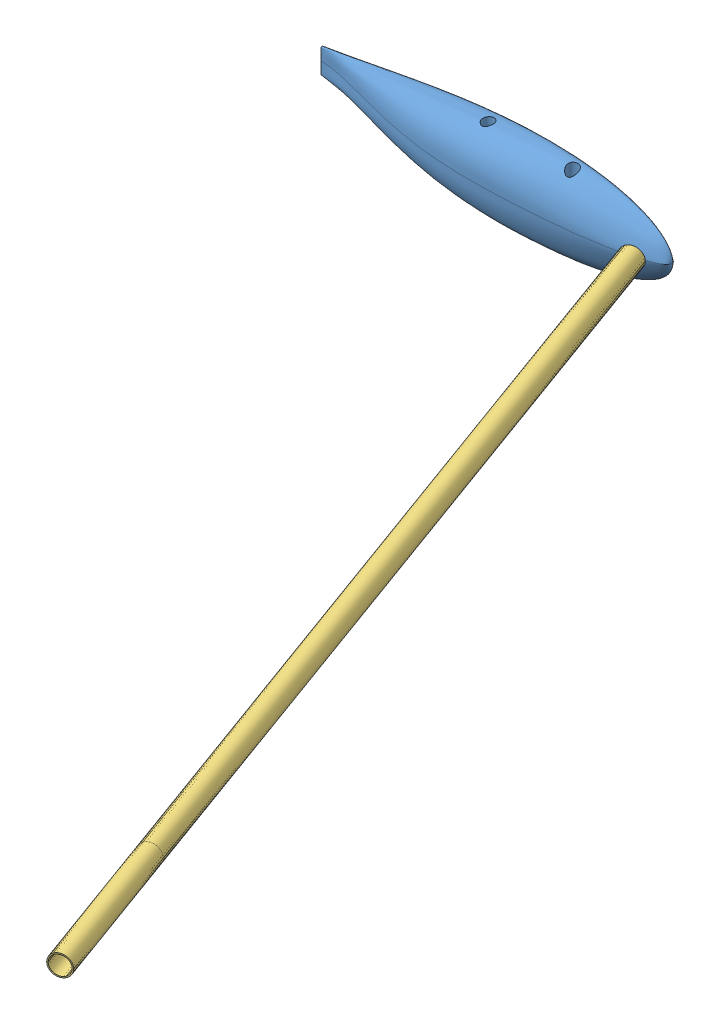
SolidWorks assembly RoundKeelCoreTest, configuration FEA. Lengths in mm.
Overall size (897.28 111.3 1260.6).
4 component instances, 3 part files, 15 mates.
Components (placement in the parent):
- Keel_bulb_Wide-1: Keel_bulb_Wide [Default] x (-1 0 0) z (0 0 -1)
- Keel_bulb_Wide-2: Keel_bulb_Wide [RightHalf] x (-1 0 0) z (0 0 -1)
- Keel_bulb_support-1: Keel_bulb_support [Default<As Machined>] at (-41.8863 0 0) x (1 0 0) z (0 -1 0)
- RoundKeelCore-1: RoundKeelCore [Default] at (-34.1794 0 21.1744) x (0 1 0) z (0.939693 0 -0.34202)
Mates (geometry in assembly coordinates):
- Coincident46: coincident anti-aligned: plane of Keel_bulb_Wide-1 through (-474.98 0 -1.2536) normal (0 -1 0); plane of Keel_bulb_Wide-2 through (-474.98 0 -1.2536) normal (0 1 0)
- Coincident145: coincident anti-aligned: plane of ? through (-25.4428 10.6172 17.3288) normal (0 -1 0); plane of Keel_bulb_support-1 through (-43.0589 10.6172 -31.071) normal (0 1 0)
- Parallel1: parallel anti-aligned: plane of ? through (-25.4428 10.6172 17.3288) normal (-0.939693 0 0.34202); plane of Keel_bulb_support-1 through (-43.0589 10.6172 -31.071) normal (0.939693 0 -0.34202)
- Concentric4: concentric anti-aligned: cylinder of ? through (-29.477 -10.8585 35.6909) axis (0 -1 0) radius 3.3782; cylinder of Keel_bulb_support-1 through (-29.477 10.6172 35.6909) axis (0 1 0) radius 2.0193
- Coincident148: coincident anti-aligned: plane of Keel_bulb_Wide-1 through (-41.8863 0 0) normal (0 0 1); plane of Keel_bulb_support-1 through (-41.8863 0 0) normal (0 0 -1)
- Coincident149: coincident anti-aligned: plane of Keel_bulb_Wide-1 through (-42.4457 9.525 -29.3861) normal (-0.939693 0 0.34202); plane of Keel_bulb_support-1 through (-42.4457 9.525 -29.3861) normal (0.939693 0 -0.34202)
- Coincident150: coincident anti-aligned: plane of Keel_bulb_Wide-2 through (-7.4567 3.3274 0) normal (0 0 1); plane of Keel_bulb_support-1 through (-41.8863 0 0) normal (0 0 -1)
- Coincident151: coincident anti-aligned: plane of Keel_bulb_Wide-2 through (-42.4457 9.525 -29.3861) normal (-0.939693 0 0.34202); plane of Keel_bulb_support-1 through (-42.4457 9.525 -29.3861) normal (0.939693 0 -0.34202)
- Coincident161: coincident anti-aligned: plane of Keel_bulb_Wide-1 through (-7.4567 3.3274 0) normal (0 -1 0); plane of Keel_bulb_support-1 through (-7.4567 3.3274 0) normal (0 1 0)
- Coincident163: coincident: point of ?
- Coincident164: coincident anti-aligned: plane of Keel_bulb_Wide-1 through (0 0 0) normal (-1 0 0); plane of assembly through (0 0 0) normal (1 0 0)
- Coincident165: coincident aligned: plane of Keel_bulb_Wide-1 through (0 0 0) normal (0 1 0); plane of assembly through (0 0 0) normal (0 1 0)
- Coincident166: coincident anti-aligned: plane of Keel_bulb_support-1 through (-60.3468 9.525 -22.8707) normal (-0.939693 0 0.34202); plane of RoundKeelCore-1 through (-30.099 0 60.2345) normal (0.939693 0 -0.34202)
- Coincident167: coincident anti-aligned: plane of Keel_bulb_support-1 through (-42.4457 9.525 -29.3861) normal (0 1 0); plane of RoundKeelCore-1 through (-21.1485 9.525 56.9767) normal (0 -1 0)
- Distance1: distance = 0.762 mm: plane of RoundKeelCore-1 through (-34.1794 0 21.1744) normal (-0.34202 0 -0.939693); point of Keel_bulb_Wide-2
